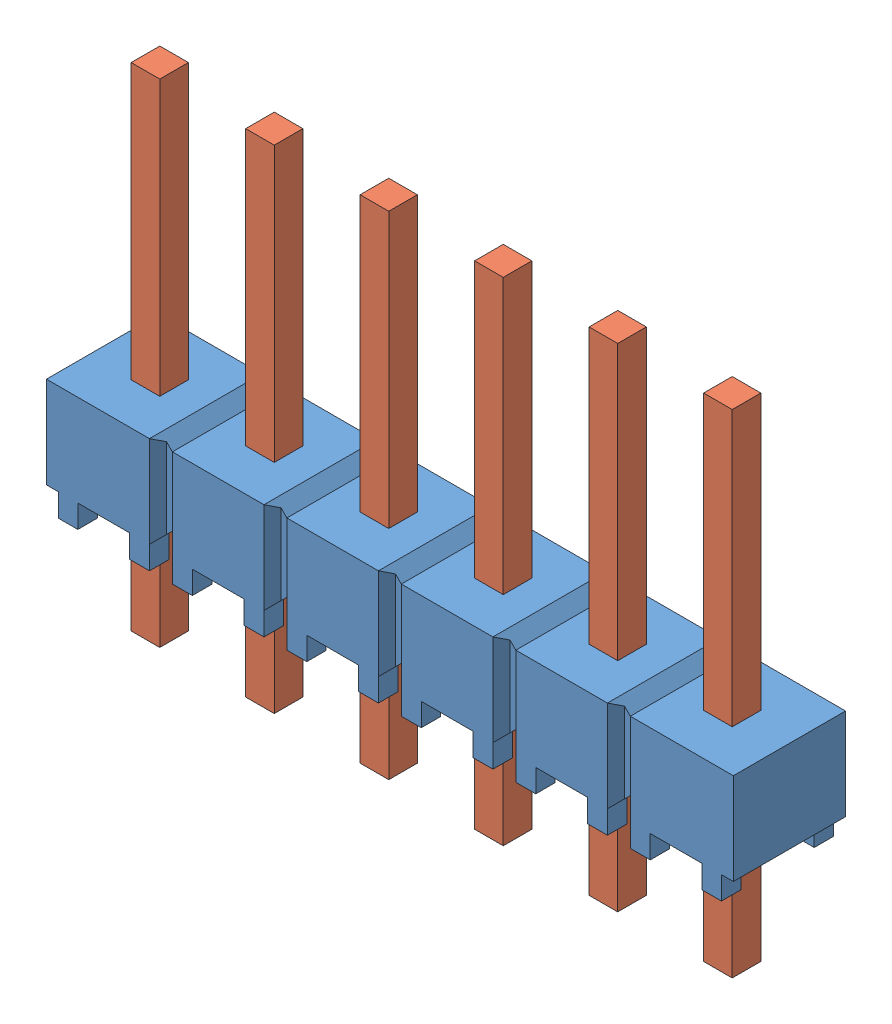
SolidWorks assembly HMTSW_106_07_G_S_240, configuration Default. Lengths in mm.
Overall size (15.24 10.92 2.49).
2 component instances, 2 part files, 0 mates.
Components (placement in the parent):
- _HMTSW_106_07_G_S_240_body_2-1: _HMTSW_106_07_G_S_240_body_2 [Default] at origin size (15.24 2.54 2.49)
- _HMTSW_106_07_S_240_4-1: _HMTSW_106_07_S_240_4 [Default] at (0 -2.286 0) size (13.59 10.92 0.89)
